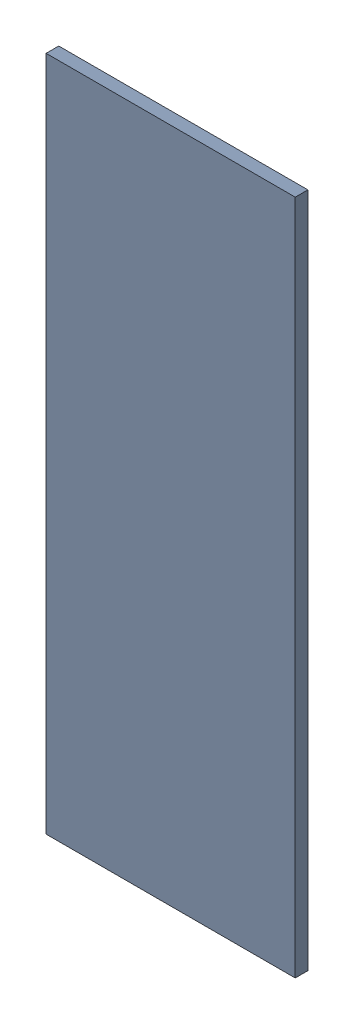
SolidWorks assembly Pad RAK4600-14(17.475mm,8.691mm) on Top Layer, configuration Predeterminado. Lengths in mm.
Overall size (0.7 1.9 0.04).
2 component instances, 1 part files, 0 mates.
Components (placement in the parent):
- Pad RAK4600-14(17.475mm,8.691mm) on Top Layer-1-1: Pad RAK4600-14(17.475mm,8.691mm) on Top Layer-1 [Predeterminado] at (-68.317 -44.187 -0.0457) size (0.7 1.9 0.04)
  - Pad RAK4600-14(17.475mm,8.691mm) on Top Layer-Part-1-1: Pad RAK4600-14(17.475mm,8.691mm) on Top Layer-Part-1 [Predeterminado] at origin size (0.7 1.9 0.04)
